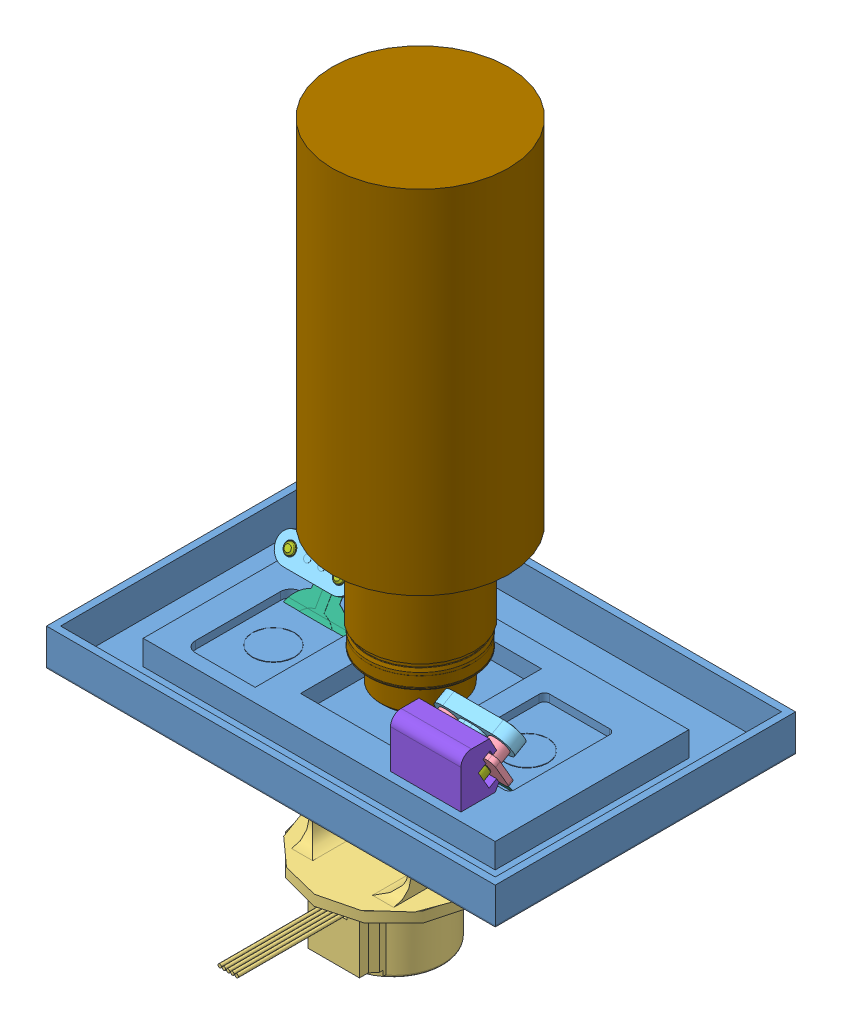
SolidWorks assembly platform-assembly, configuration Default. Lengths in mm.
Overall size (100 198.01 80.85).
22 component instances, 12 part files, 8 mates.
Components (placement in the parent):
- device-1: device [Default] at (5.4712 6.5578 2.6553) size (127.5 10.3 85.3)
- rotation-assembly-2: rotation-assembly [Default] at (-32.6093 -41.4511 -84.9768) size (26 29.9 16.8)
- rotation-stand-1: rotation-stand [Varsayılan] at (5.4702 -26.7422 10.4316) x (-1 0 0) z (0 -1 0) size (45 69.5 52)
- confocal-stand-1: confocal-stand [Default] at (5.4712 4.7578 2.5599) x (0 0 1) z (-1 0 0) size (95.3 4.5 167.5) (hidden)
- electrode-assembly-1: electrode-assembly [Default] at (-8.5375 31.28 -9.2524) x (1 0 0) z (0 -0.866025 0.5) size (25 21.42 33.61)
  - PogoPin_M3Screw_Adapter-1: PogoPin_M3Screw_Adapter [Default] at (-18.0083 -3.1612 9.7821) size (25 5.5 10)
  - MilliMax_PogoPin_858-10-002-30-001101-1: MilliMax_PogoPin_858-10-002-30-001101 [Default] at (-17.9573 6.098 9.7821) x (-1 0 0) z (0 0 1) size (22 8.98 8)
  - LIG_EMG_v2-1: LIG_EMG_v2 [Default] at (229.448 -1.7362 44.5058) x (0 0 -1) z (1 0 0) size (29.17 0.16 20) (hidden)
  - LIG_EMG_v2_bent-1: LIG_EMG_v2_bent [Default] at (229.448 -1.7362 44.5058) x (0 0 -1) z (1 0 0) size (24.73 9.28 20.06)
  - 93640A125_Nylon Plastic Socket Head Screw-1: 93640A125_Nylon Plastic Socket Head Screw [93640A125] at (-10.9583 6.8388 9.7821) x (0 0 -1) z (0 1 0) size (4.6 4.6 13.01)
  - 93640A125_Nylon Plastic Socket Head Screw-2: 93640A125_Nylon Plastic Socket Head Screw [93640A125] at (-24.9583 6.8388 9.7821) x (0 0 -1) z (0 1 0) size (4.6 4.6 13.01)
  - electrode-holder-2: electrode-holder [Default] at (13.7917 -4.2307 26.3837) x (1 0 0) z (0 0.866025 0.5) size (20 14 10.84)
- electrode-assembly-2: electrode-assembly [Default] at (17.4852 31.28 24.384) x (-1 0 0) z (0 -0.866025 -0.5) size (25 21.42 33.61)
  - PogoPin_M3Screw_Adapter-1: PogoPin_M3Screw_Adapter [Default] at (-18.0083 -3.1612 9.7821) size (25 5.5 10)
  - MilliMax_PogoPin_858-10-002-30-001101-1: MilliMax_PogoPin_858-10-002-30-001101 [Default] at (-17.9573 6.098 9.7821) x (-1 0 0) z (0 0 1) size (22 8.98 8)
  - LIG_EMG_v2-1: LIG_EMG_v2 [Default] at (229.448 -1.7362 44.5058) x (0 0 -1) z (1 0 0) size (29.17 0.16 20) (hidden)
  - LIG_EMG_v2_bent-1: LIG_EMG_v2_bent [Default] at (229.448 -1.7362 44.5058) x (0 0 -1) z (1 0 0) size (24.73 9.28 20.06)
  - 93640A125_Nylon Plastic Socket Head Screw-1: 93640A125_Nylon Plastic Socket Head Screw [93640A125] at (-10.9583 6.8388 9.7821) x (0 0 -1) z (0 1 0) size (4.6 4.6 13.01)
  - 93640A125_Nylon Plastic Socket Head Screw-2: 93640A125_Nylon Plastic Socket Head Screw [93640A125] at (-24.9583 6.8388 9.7821) x (0 0 -1) z (0 1 0) size (4.6 4.6 13.01)
  - electrode-holder-2: electrode-holder [Default] at (13.7917 -4.2307 26.3837) x (1 0 0) z (0 0.866025 0.5) size (20 14 10.84)
- device-peeled-1: device-peeled [bend2] at (5.6806 6.6623 3.0556) size (127.5 63.13 85.3) (hidden)
- objective-1: objective [Default] at (5.4242 9.4338 2.8157) size (50 142.83 50)
Mates (geometry in assembly coordinates):
- Coincident1: coincident: plane of rotation-deviceonly-1 through (5.4712 6.7578 2.6553) normal (0 1 0); plane of rotation-assembly-2-2 through (-32.7087 6.7578 -84.9768) normal (0 -1 0)
- Coincident2: coincident: plane of rotation-assembly-2-2 through (4.5584 -18.0937 0.9316) normal (0 0 1); plane of rotation-stand-1 through (3.4702 -20.8418 0.9316) normal (0 0 -1)
- Parallel1: parallel: plane of rotation-assembly-2-2 through (4.5584 -18.0937 4.1316) normal (0 0 -1); plane of rotation-stand-1 through (3.4702 -20.8418 3.9316) normal (0 0 1)
- Coincident3: coincident anti-aligned: plane of rotation-deviceonly-1 through (5.4712 6.2578 2.6553) normal (0 -1 0); plane of confocal-stand-1 through (5.4712 6.2578 2.5599) normal (0 1 0)
- Coincident5: coincident aligned: plane of rotation-stand-1 through (5.4702 4.7578 10.4316) normal (0 -1 0); plane of confocal-stand-1 through (5.4712 4.7578 2.5599) normal (0 -1 0)
- Distance1: distance = 0.5 mm anti-aligned: plane of confocal-stand-1 through (-58.7788 9.2578 2.5599) normal (1 0 0); plane of rotation-deviceonly-1 through (-58.2788 6.2578 -39.9947) normal (-1 0 0)
- Coincident8: coincident: plane of rotation-assembly-2-2 through (1.7197 -22.7422 2.5316) normal (0 -1 0); plane of rotation-stand-1 through (5.4702 -22.7422 2.4316) normal (0 1 0)
- Coincident9: coincident anti-aligned: plane of rotation-assembly-2-2 through (1.4476 -22.7422 2.5316) normal (0 -1 0); plane of rotation-stand-1 through (5.4702 -22.7422 2.4316) normal (0 1 0)
